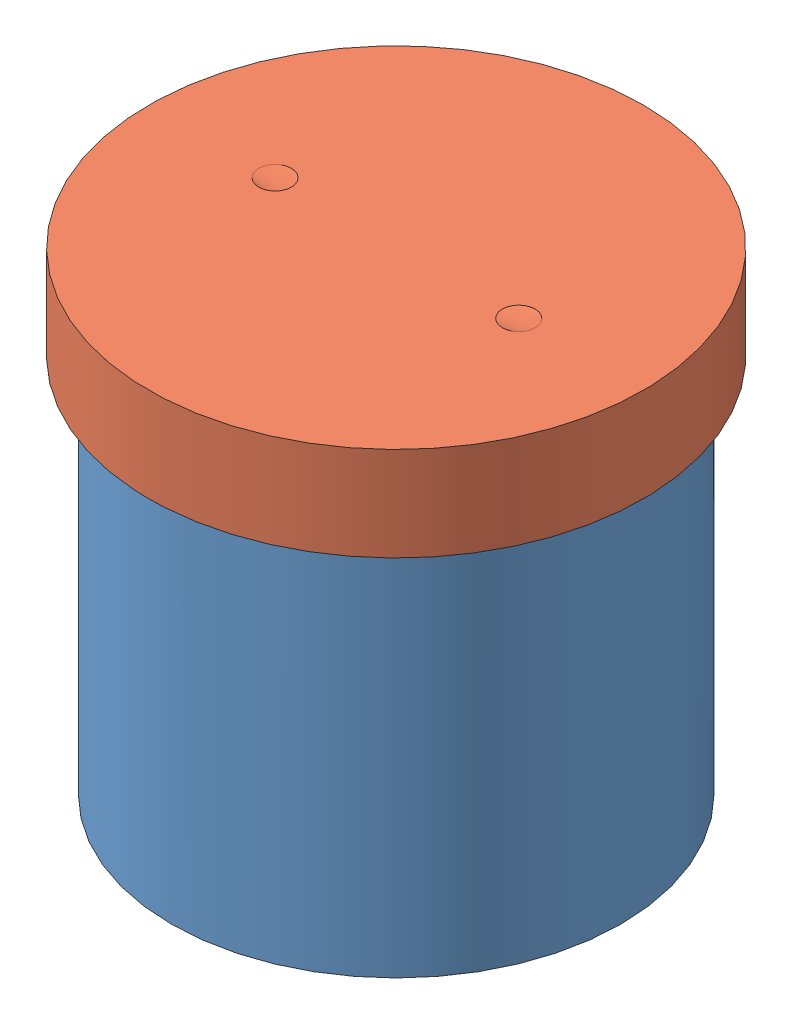
SolidWorks assembly tank_assem, configuration Default. Lengths in mm.
Overall size (121 127.9 121).
4 component instances, 4 part files, 9 mates.
Components (placement in the parent):
- tank_body-1: tank_body [Default] at origin size (110 110.17 112.27)
- tank_cap-1: tank_cap [Default] at (0 102.0838 0) x (-1 0 0) z (0 0 1) size (121 23 121)
- tank_body_fitting_mount-1: tank_body_fitting_mount [Default] at (0 -8.8163 0) x (1 0 0) z (0 -1 0) size (22 22 17)
- brass_fitting_joint_noprint-1: brass_fitting_joint_noprint [Default] at (0 -16.8163 0) x (-0.837169 0 -0.546944) z (0 1 0) size (23.09 20.21 12)
Mates (geometry in assembly coordinates):
- Coincident1: coincident: plane of assembly through (0 0 0) normal (0 0 1); plane of tank_body-1 through (0 0 0) normal (0 0 1); plane of assembly
- Coincident2: coincident aligned: plane of tank_cap-1 through (0 102.0838 0) normal (0 0 1)
- Concentric1: concentric anti-aligned: cylinder of tank_body-1 through (0 100 0) axis (0 -1 0) radius 55; cylinder of tank_cap-1 through (0 84.0838 0) axis (0 1 0) radius 60.5
- Distance1: distance = 16.6465 mm anti-aligned: plane of tank_cap-1 through (0 84.0838 0) normal (0 -1 0); plane of tank_body-1 through (0 100 0) normal (0 1 0)
- Concentric2: concentric anti-aligned: cylinder of tank_body-1 through (0 100 0) axis (0 -1 0) radius 55; cylinder of tank_body_fitting_mount-1 through (0 -16.8163 0) axis (0 1 0) radius 11
- Coincident4: coincident anti-aligned: plane of tank_body-1 through (11 101.3498 2.05) normal (-1 0 0); plane of tank_body_fitting_mount-1 through (11 -8.8163 2) normal (1 0 0)
- Coincident5: coincident anti-aligned: plane of tank_body-1 through (0 -8.8163 0) normal (0 -1 0); plane of tank_body_fitting_mount-1 through (0 -8.8163 0) normal (0 1 0)
- Concentric3: concentric aligned: cylinder of tank_body_fitting_mount-1 through (0 -16.8163 0) axis (0 1 0) radius 11; circle of brass_fitting_joint_noprint-1
- Coincident6: coincident anti-aligned: plane of tank_body_fitting_mount-1 through (0 -16.8163 0) normal (0 -1 0); plane of brass_fitting_joint_noprint-1 through (0 -16.8163 0) normal (0 1 0)
